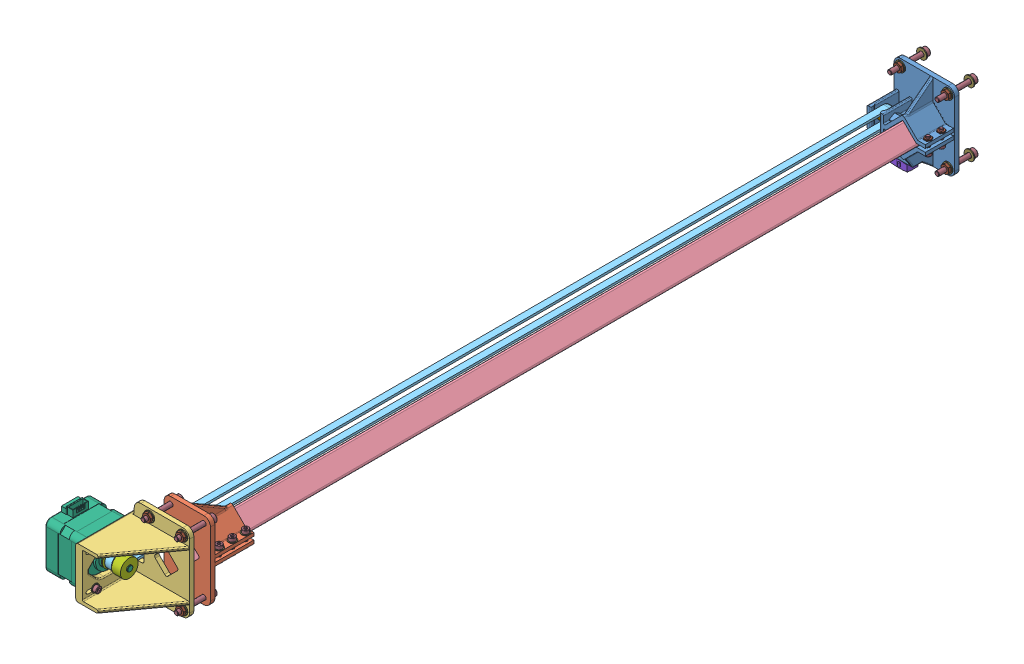
SolidWorks assembly Tower Assy, configuration Default. Lengths in mm.
Overall size (89.12 70.66 764.8).
74 component instances, 13 part files, 76 mates.
Components (placement in the parent):
- tube clamp Top-1: tube clamp Top [Default] at (0 0 -4) x (0 1 0) z (0 0 1) size (70 55 30)
- tube clamp bottom-1: tube clamp bottom [Default] at (0 0 674) x (0 -1 0) z (0 0 -1) size (70 42 40)
- Motor Mount-1: Motor Mount [Default] at (-4 0 689) x (0 1 0) z (0 0 1) size (70 55 52)
- beam-1: beam [Default] x (0.707107 0.707107 0) z (0 0 1) size (19 19 670)
- belt-1: belt [Default] at (-24.75 0 714) x (-1 0 0) z (0 -1 0) size (6 712 14)
- User Library-037_45_074     step motor_-1: User Library-037_45_074     step motor_ [Default] at (-34 0 714) x (-1 0 0) z (0 0 1) size (56 48 42)
- HTPA20S2M060_K_H5_a-1: HTPA20S2M060_K_H5_a [Default] at (-30.5 0 714) x (1 0 0) z (0 0.276501 0.961014) size (18 16 16)
- V4 Microswitch-1: V4 Microswitch [Default] at (-13.75 -30.2 8.3) x (-1 0 0) z (0 1 0) size (19.8 16 6.4)
- radial ball bearing_68_skf-11: radial ball bearing_68_skf [SKF - 623 - 8,SI,NC,8_68] at (-23 0 16) x (-1 0 0) z (0 -0.940463 -0.339896) size (4 10 10)
- radial ball bearing_68_skf-12: radial ball bearing_68_skf [SKF - 623 - 8,SI,NC,8_68] at (-27 0 16) x (-1 0 0) z (0 0.019127 -0.999817) size (4 10 10)
- pan head cross recess screw_din-14: pan head cross recess screw_din [ISO 7045 - M3 x 20 - Z --- 20N] at (-35.4 0 16) x (1 0 0) z (0 0.823751 -0.566952) size (22.35 5.6 5.6)
- hex thin nut chamfered gradeab_din-14: hex thin nut chamfered gradeab_din [Hexagon Thin Nut ISO 4035 - M3 - N] at (-17.5 0 16) x (0 -0.866025 -0.5) z (-1 0 0) size (5.5 6.35 1.8)
- plain washer grade a_din-25: plain washer grade a_din [Washer DIN 125 - A 3.2] at (-32.5 0 16) x (1 0 0) z (0 0.074713 0.997205) size (0.5 7 7)
- plain washer grade a_din-26: plain washer grade a_din [Washer DIN 125 - A 3.2] at (-20.5 0 16) x (1 0 0) z (0 0.074713 0.997205) size (0.5 7 7)
- plain washer grade a_din-27: plain washer grade a_din [Washer DIN 125 - A 3.2] at (-29 0 16) x (1 0 0) z (0 0.074713 0.997205) size (0.5 7 7)
- plain washer grade a_din-28: plain washer grade a_din [Washer DIN 125 - A 3.2] at (-27.5 -15.5 698.5) x (1 0 0) z (0 0.074713 0.997205) size (0.5 7 7)
- socket head cap screw 4762_din-15: socket head cap screw 4762_din [ISO 4762 M3 x 10 --- 10N] at (-24.5 -15.5 698.5) x (-1 0 0) z (0 -0.699814 0.714325) size (13 5.5 5.5)
- plain washer grade a_din-29: plain washer grade a_din [Washer DIN 125 - A 4.3] at (15 29 693.8) x (0 0 1) z (-0.172888 -0.984942 0) size (0.8 9 9)
- socket head cap screw 4762_din-16: socket head cap screw 4762_din [ISO 4762 M4 x 30 --- 20N] at (15 29 665.2) x (0 0 1) z (-0.929203 -0.369569 0) size (34 7 7)
- hex thin nut chamfered gradeab_din-15: hex thin nut chamfered gradeab_din [Hexagon Thin Nut ISO 4035 - M4 - N] at (15 29 696) x (-0.973232 0.229826 0) z (0 0 1) size (7 8.08 2.2)
- plain washer grade a_din-30: plain washer grade a_din [Washer DIN 125 - A 4.3] at (15 29 670) x (0 0 1) z (-0.172888 -0.984942 0) size (0.8 9 9)
- plain washer grade a_din-31: plain washer grade a_din [Washer DIN 125 - A 4.3] at (-15 29 670) x (0 0 1) z (-0.172888 -0.984942 0) size (0.8 9 9)
- plain washer grade a_din-32: plain washer grade a_din [Washer DIN 125 - A 4.3] at (15 -29 670) x (0 0 1) z (-0.172888 -0.984942 0) size (0.8 9 9)
- plain washer grade a_din-33: plain washer grade a_din [Washer DIN 125 - A 4.3] at (-15 -29 670) x (0 0 1) z (-0.172888 -0.984942 0) size (0.8 9 9)
- plain washer grade a_din-34: plain washer grade a_din [Washer DIN 125 - A 4.3] at (-15 29 693.8) x (0 0 1) z (-0.172888 -0.984942 0) size (0.8 9 9)
- plain washer grade a_din-35: plain washer grade a_din [Washer DIN 125 - A 4.3] at (15 -29 693.8) x (0 0 1) z (-0.172888 -0.984942 0) size (0.8 9 9)
- plain washer grade a_din-36: plain washer grade a_din [Washer DIN 125 - A 4.3] at (-15 -29 693.8) x (0 0 1) z (-0.172888 -0.984942 0) size (0.8 9 9)
- hex thin nut chamfered gradeab_din-16: hex thin nut chamfered gradeab_din [Hexagon Thin Nut ISO 4035 - M4 - N] at (-15 29 696) x (-0.973232 0.229826 0) z (0 0 1) size (7 8.08 2.2)
- hex thin nut chamfered gradeab_din-17: hex thin nut chamfered gradeab_din [Hexagon Thin Nut ISO 4035 - M4 - N] at (15 -29 696) x (-0.973232 0.229826 0) z (0 0 1) size (7 8.08 2.2)
- hex thin nut chamfered gradeab_din-18: hex thin nut chamfered gradeab_din [Hexagon Thin Nut ISO 4035 - M4 - N] at (-15 -29 696) x (-0.973232 0.229826 0) z (0 0 1) size (7 8.08 2.2)
- socket head cap screw 4762_din-17: socket head cap screw 4762_din [ISO 4762 M4 x 30 --- 20N] at (-15 29 665.2) x (0 0 1) z (-0.929203 -0.369569 0) size (34 7 7)
- socket head cap screw 4762_din-18: socket head cap screw 4762_din [ISO 4762 M4 x 30 --- 20N] at (15 -29 665.2) x (0 0 1) z (-0.929203 -0.369569 0) size (34 7 7)
- socket head cap screw 4762_din-19: socket head cap screw 4762_din [ISO 4762 M4 x 30 --- 20N] at (-15 -29 665.2) x (0 0 1) z (-0.929203 -0.369569 0) size (34 7 7)
- plain washer grade a_din-37: plain washer grade a_din [Washer DIN 125 - A 3.2] at (-27.5 -15.5 729.5) x (1 0 0) z (0 0.074713 0.997205) size (0.5 7 7)
- plain washer grade a_din-38: plain washer grade a_din [Washer DIN 125 - A 3.2] at (-27.5 15.5 698.5) x (1 0 0) z (0 0.074713 0.997205) size (0.5 7 7)
- plain washer grade a_din-39: plain washer grade a_din [Washer DIN 125 - A 3.2] at (-27.5 15.5 729.5) x (1 0 0) z (0 0.074713 0.997205) size (0.5 7 7)
- socket head cap screw 4762_din-20: socket head cap screw 4762_din [ISO 4762 M3 x 10 --- 10N] at (-24.5 -15.5 729.5) x (-1 0 0) z (0 -0.699814 0.714325) size (13 5.5 5.5)
- socket head cap screw 4762_din-21: socket head cap screw 4762_din [ISO 4762 M3 x 10 --- 10N] at (-24.5 15.5 698.5) x (-1 0 0) z (0 -0.699814 0.714325) size (13 5.5 5.5)
- socket head cap screw 4762_din-22: socket head cap screw 4762_din [ISO 4762 M3 x 10 --- 10N] at (-24.5 15.5 729.5) x (-1 0 0) z (0 -0.699814 0.714325) size (13 5.5 5.5)
- socket head cap screw 4762_din-23: socket head cap screw 4762_din [ISO 4762 M3 x 12 --- 12N] at (16.8191 8 662) x (0 -1 0) z (-0.921576 0 0.388197) size (15 5.5 5.5)
- plain washer grade a_din-40: plain washer grade a_din [Washer DIN 125 - A 3.2] at (16.8191 4.5 662) x (0 -1 0) z (-0.85738 0 -0.514684) size (0.5 7 7)
- hex thin nut chamfered gradeab_din-19: hex thin nut chamfered gradeab_din [Hexagon Thin Nut ISO 4035 - M3 - N] at (16.8191 -5.3 662) x (-0.866025 0 0.5) z (0 -1 0) size (5.5 6.35 1.8)
- plain washer grade a_din-41: plain washer grade a_din [Washer DIN 125 - A 3.2] at (16.8191 4.5 650) x (0 -1 0) z (-0.85738 0 -0.514684) size (0.5 7 7)
- plain washer grade a_din-42: plain washer grade a_din [Washer DIN 125 - A 3.2] at (16.8191 4.5 638) x (0 -1 0) z (-0.85738 0 -0.514684) size (0.5 7 7)
- hex thin nut chamfered gradeab_din-20: hex thin nut chamfered gradeab_din [Hexagon Thin Nut ISO 4035 - M3 - N] at (16.8191 -5.3 650) x (-0.866025 0 0.5) z (0 -1 0) size (5.5 6.35 1.8)
- hex thin nut chamfered gradeab_din-21: hex thin nut chamfered gradeab_din [Hexagon Thin Nut ISO 4035 - M3 - N] at (16.8191 -5.3 638) x (-0.866025 0 0.5) z (0 -1 0) size (5.5 6.35 1.8)
- socket head cap screw 4762_din-24: socket head cap screw 4762_din [ISO 4762 M3 x 12 --- 12N] at (16.8191 8 650) x (0 -1 0) z (-0.921576 0 0.388197) size (15 5.5 5.5)
- socket head cap screw 4762_din-25: socket head cap screw 4762_din [ISO 4762 M3 x 12 --- 12N] at (16.8191 8 638) x (0 -1 0) z (-0.921576 0 0.388197) size (15 5.5 5.5)
- socket head cap screw 4762_din-26: socket head cap screw 4762_din [ISO 4762 M3 x 12 --- 12N] at (16.8191 -8 8) x (0 1 0) z (0.559193 0 0.829037) size (15 5.5 5.5)
- hex thin nut chamfered gradeab_din-22: hex thin nut chamfered gradeab_din [Hexagon Thin Nut ISO 4035 - M3 - N] at (16.8191 3.5 8) x (0 0 1) z (0 -1 0) size (5.5 6.35 1.8)
- plain washer grade a_din-43: plain washer grade a_din [Washer DIN 125 - A 3.2] at (16.8191 -5 8) x (0 -1 0) z (-0.85738 0 -0.514684) size (0.5 7 7)
- plain washer grade a_din-44: plain washer grade a_din [Washer DIN 125 - A 3.2] at (16.8191 -5 20) x (0 -1 0) z (-0.85738 0 -0.514684) size (0.5 7 7)
- hex thin nut chamfered gradeab_din-23: hex thin nut chamfered gradeab_din [Hexagon Thin Nut ISO 4035 - M3 - N] at (16.8191 3.5 20) x (0 0 1) z (0 -1 0) size (5.5 6.35 1.8)
- socket head cap screw 4762_din-27: socket head cap screw 4762_din [ISO 4762 M3 x 12 --- 12N] at (16.8191 -8 20) x (0 1 0) z (0.559193 0 0.829037) size (15 5.5 5.5)
- socket head cap screw 4762_din-28: socket head cap screw 4762_din [ISO 4762 M4 x 30 --- 20N] at (-28 -29 -23.8) x (0 0 1) z (0.194578 0.980887 0) size (34 7 7)
- plain washer grade a_din-45: plain washer grade a_din [Washer DIN 125 - A 4.3] at (-28 -29 -19.8) x (0 0 -1) z (-0.536982 0.843594 0) size (0.8 9 9)
- hex thin nut chamfered gradeab_din-24: hex thin nut chamfered gradeab_din [Hexagon Thin Nut ISO 4035 - M4 - N] at (-28 -29 0.8) x (-0.988084 -0.153918 0) z (0 0 -1) size (7 8.08 2.2)
- hex thin nut chamfered gradeab_din-25: hex thin nut chamfered gradeab_din [Hexagon Thin Nut ISO 4035 - M4 - N] at (15 -29 0.8) x (-0.988084 -0.153918 0) z (0 0 -1) size (7 8.08 2.2)
- hex thin nut chamfered gradeab_din-26: hex thin nut chamfered gradeab_din [Hexagon Thin Nut ISO 4035 - M4 - N] at (15 29 0.8) x (-0.988084 -0.153918 0) z (0 0 -1) size (7 8.08 2.2)
- hex thin nut chamfered gradeab_din-27: hex thin nut chamfered gradeab_din [Hexagon Thin Nut ISO 4035 - M4 - N] at (-28 29 0.8) x (-0.988084 -0.153918 0) z (0 0 -1) size (7 8.08 2.2)
- plain washer grade a_din-46: plain washer grade a_din [Washer DIN 125 - A 4.3] at (15 -29 -19.8) x (0 0 -1) z (-0.536982 0.843594 0) size (0.8 9 9)
- plain washer grade a_din-47: plain washer grade a_din [Washer DIN 125 - A 4.3] at (15 29 -19.8) x (0 0 -1) z (-0.536982 0.843594 0) size (0.8 9 9)
- plain washer grade a_din-48: plain washer grade a_din [Washer DIN 125 - A 4.3] at (-28 29 -19.8) x (0 0 -1) z (-0.536982 0.843594 0) size (0.8 9 9)
- socket head cap screw 4762_din-29: socket head cap screw 4762_din [ISO 4762 M4 x 30 --- 20N] at (15 -29 -23.8) x (0 0 1) z (0.194578 0.980887 0) size (34 7 7)
- socket head cap screw 4762_din-30: socket head cap screw 4762_din [ISO 4762 M4 x 30 --- 20N] at (15 29 -23.8) x (0 0 1) z (0.194578 0.980887 0) size (34 7 7)
- socket head cap screw 4762_din-31: socket head cap screw 4762_din [ISO 4762 M4 x 30 --- 20N] at (-28 29 -23.8) x (0 0 1) z (0.194578 0.980887 0) size (34 7 7)
- plain washer grade a_din-49: plain washer grade a_din [Washer DIN 125 - A 4.3] at (-28 -29 0) x (0 0 -1) z (-0.185185 0.982704 0) size (0.8 9 9)
- plain washer grade a_din-50: plain washer grade a_din [Washer DIN 125 - A 4.3] at (15 -29 0) x (0 0 -1) z (-0.185185 0.982704 0) size (0.8 9 9)
- plain washer grade a_din-51: plain washer grade a_din [Washer DIN 125 - A 4.3] at (15 29 0) x (0 0 -1) z (-0.185185 0.982704 0) size (0.8 9 9)
- plain washer grade a_din-52: plain washer grade a_din [Washer DIN 125 - A 4.3] at (-28 29 0) x (0 0 -1) z (-0.185185 0.982704 0) size (0.8 9 9)
- pan head cross recess screw_din-1: pan head cross recess screw_din [ISO 7045 - M2.5 x 12 - Z --- 12N] at (-9 -35.5 10.5) x (0 1 0) z (-1 0 0) size (14.05 5 5)
- pan head cross recess screw_din-2: pan head cross recess screw_din [ISO 7045 - M2.5 x 12 - Z --- 12N] at (-18.5 -35.5 10.5) x (0 1 0) z (0 0 1) size (14.05 5 5)
- hex thin nut chamfered gradeab_din-28: hex thin nut chamfered gradeab_din [Hexagon Thin Nut ISO 4035 - M2.5 - N] at (-18.5 -24 10.5) x (0 0 1) z (0 -1 0) size (5 5.77 1.6)
- hex thin nut chamfered gradeab_din-29: hex thin nut chamfered gradeab_din [Hexagon Thin Nut ISO 4035 - M2.5 - N] at (-9 -24 10.5) x (0 0 1) z (0 -1 0) size (5 5.77 1.6)
Mates (geometry in assembly coordinates):
- Coincident5: coincident aligned: plane of beam-1 through (0 0 0) normal (0 0 1); plane of assembly through (0 0 0) normal (0 0 1)
- Coincident6: coincident aligned: plane of beam-1; plane of assembly through (0 0 0) normal (1 0 0)
- Coincident7: coincident: point of beam-1; plane of assembly
- Coincident45: coincident anti-aligned: plane of beam-1 through (0 -11.3137 670) normal (0 0 1); plane of tube clamp bottom-1 through (0 0 670) normal (0 0 -1)
- Coincident49: coincident anti-aligned: plane of belt-1 through (-24.75 0 714) normal (0 -1 0); plane of assembly through (0 0 0) normal (0 1 0)
- Concentric25: concentric aligned: cylinder of HTPA20S2M060_K_H5_a-1 through (-11.5 0 714) axis (-1 0 0) radius 2.5; cylinder of User Library-037_45_074     step motor_-1 through (-11.5 0 714) axis (-1 0 0) radius 2.5
- Distance3: distance = 1 mm aligned: plane of HTPA20S2M060_K_H5_a-1 through (-12.5 2.4025 713.3087) normal (1 0 0); plane of User Library-037_45_074     step motor_-1 through (-11.5 0 714) normal (1 0 0)
- Concentric26: concentric anti-aligned: cylinder of belt-1 through (-27.75 0 714) axis (1 0 0) radius 7; cylinder of User Library-037_45_074     step motor_-1 through (-11.5 0 714) axis (-1 0 0) radius 2.5
- Concentric27: concentric aligned: cylinder of radial ball bearing_68_skf-11 through (-2.3625 0 16) axis (-1 0 0) radius 1.5; cylinder of radial ball bearing_68_skf-12 through (-6.3625 0 16) axis (-1 0 0) radius 1.5
- Coincident57: coincident anti-aligned: plane of radial ball bearing_68_skf-11 through (-25 0.5608 14.4482) normal (-1 0 0); plane of radial ball bearing_68_skf-12 through (-25 2.5495 16.0488) normal (1 0 0)
- Concentric29: concentric anti-aligned: cylinder of belt-1 through (-27.75 0 16) axis (1 0 0) radius 5; cylinder of radial ball bearing_68_skf-12 through (-6.3625 0 16) axis (-1 0 0) radius 5
- Concentric30: concentric aligned: cylinder of radial ball bearing_68_skf-12 through (-6.3625 0 16) axis (-1 0 0) radius 1.5; cylinder of pan head cross recess screw_din-14 through (-60.8 0 16) axis (-1 0 0) radius 1.5
- Coincident61: coincident anti-aligned: plane of tube clamp Top-1 through (-32.5 -9.1582 26) normal (-1 0 0); plane of plain washer grade a_din-25 through (-32.5 1.5955 15.8805) normal (1 0 0)
- Concentric31: concentric aligned: cylinder of pan head cross recess screw_din-14 through (-60.8 0 16) axis (-1 0 0) radius 1.5; cylinder of plain washer grade a_din-25 through (-67.425 0 16) axis (-1 0 0) radius 1.6
- Coincident62: coincident anti-aligned: plane of pan head cross recess screw_din-14 through (-33 -0.8504 14.7644) normal (1 0 0); plane of plain washer grade a_din-25 through (-33 3.4902 15.7385) normal (-1 0 0)
- Concentric32: concentric aligned: cylinder of pan head cross recess screw_din-14 through (-60.8 0 16) axis (-1 0 0) radius 1.5; cylinder of hex thin nut chamfered gradeab_din-14 through (-15.7 0 16) axis (-1 0 0) radius 1.25
- Coincident63: coincident anti-aligned: plane of tube clamp Top-1 through (-17.5 -9.1582 26) normal (1 0 0); plane of hex thin nut chamfered gradeab_din-14 through (-17.5 -1.5877 18.75) normal (-1 0 0)
- Concentric33: concentric aligned: line of tube clamp Top-1 through (-8.6782 0 16) axis (-1 0 0); cylinder of pan head cross recess screw_din-14 through (-60.8 0 16) axis (-1 0 0) radius 1.5
- Coincident65: coincident anti-aligned: plane of radial ball bearing_68_skf-12 through (-29 1.6497 16.0316) normal (-1 0 0); plane of plain washer grade a_din-27 through (-29 1.5955 15.8805) normal (1 0 0)
- Coincident66: coincident anti-aligned: plane of radial ball bearing_68_skf-11 through (-21 0.8667 13.6018) normal (1 0 0); plane of plain washer grade a_din-26 through (-21 3.4902 15.7385) normal (-1 0 0)
- Concentric34: concentric aligned: cylinder of radial ball bearing_68_skf-11 through (-2.3625 0 16) axis (-1 0 0) radius 1.5; cylinder of plain washer grade a_din-26 through (-55.425 0 16) axis (-1 0 0) radius 1.6
- Concentric35: concentric aligned: cylinder of radial ball bearing_68_skf-12 through (-6.3625 0 16) axis (-1 0 0) radius 1.5; cylinder of plain washer grade a_din-27 through (-63.925 0 16) axis (-1 0 0) radius 1.6
- Coincident67: coincident anti-aligned: plane of tube clamp Top-1 through (-29.5 -9.1582 26) normal (1 0 0); plane of plain washer grade a_din-27 through (-29.5 3.4902 15.7385) normal (-1 0 0)
- Distance5: distance = 15 mm anti-aligned: plane of tube clamp bottom-1 through (0 0 674) normal (0 0 1); plane of Motor Mount-1 through (-4 0 689) normal (0 0 -1)
- Coincident69: coincident aligned: plane of Motor Mount-1; plane of assembly through (0 0 0) normal (0 1 0)
- Concentric36: concentric anti-aligned: cylinder of tube clamp bottom-1 through (15 29 670) axis (0 0 -1) radius 2.1; cylinder of Motor Mount-1 through (15 29 693) axis (0 0 1) radius 2.1
- Coincident73: coincident anti-aligned: plane of User Library-037_45_074     step motor_-1 through (-34 -21 693) normal (1 0 0); plane of Motor Mount-1 through (-34 -23 741) normal (-1 0 0)
- Parallel7: parallel aligned: plane of Motor Mount-1 through (-4 0 693) normal (0 0 1); plane of User Library-037_45_074     step motor_-1 through (-67.5 21 735) normal (0 0 1)
- Coincident75: coincident anti-aligned: plane of Motor Mount-1 through (-28 -20 741) normal (1 0 0); plane of plain washer grade a_din-28 through (-28 -12.0098 698.2385) normal (-1 0 0)
- Concentric39: concentric anti-aligned: cylinder of User Library-037_45_074     step motor_-1 through (-67.5 -15.5 698.5) axis (1 0 0) radius 1.6; cylinder of plain washer grade a_din-28 through (-62.425 -15.5 698.5) axis (-1 0 0) radius 1.6
- Concentric40: concentric anti-aligned: cylinder of plain washer grade a_din-28 through (-62.425 -15.5 698.5) axis (-1 0 0) radius 1.6; cylinder of socket head cap screw 4762_din-15 through (7.25 -15.5 698.5) axis (1 0 0) radius 1.5
- Coincident76: coincident anti-aligned: plane of plain washer grade a_din-28 through (-27.5 -13.9045 698.3805) normal (1 0 0); plane of socket head cap screw 4762_din-15 through (-27.5 -17.4644 696.5755) normal (-1 0 0)
- Concentric41: concentric anti-aligned: cylinder of Motor Mount-1 through (15 29 693) axis (0 0 1) radius 2.1; cylinder of plain washer grade a_din-29 through (15 29 658.875) axis (0 0 -1) radius 2.15
- Coincident77: coincident anti-aligned: plane of Motor Mount-1 through (-4 0 693) normal (0 0 1); plane of plain washer grade a_din-29 through (10.5678 29.778 693) normal (0 0 -1)
- Concentric42: concentric aligned: cylinder of tube clamp bottom-1 through (15 29 670) axis (0 0 -1) radius 2.1; cylinder of socket head cap screw 4762_din-16 through (15 29 633.45) axis (0 0 -1) radius 2
- Concentric43: concentric anti-aligned: cylinder of socket head cap screw 4762_din-16 through (15 29 633.45) axis (0 0 -1) radius 2; cylinder of hex thin nut chamfered gradeab_din-15 through (15 29 693.8) axis (0 0 1) radius 1.65
- Coincident78: coincident anti-aligned: plane of plain washer grade a_din-29 through (12.8824 29.3717 693.8) normal (0 0 1); plane of hex thin nut chamfered gradeab_din-15 through (21.8126 27.3912 693.8) normal (0 0 -1)
- Concentric44: concentric aligned: cylinder of socket head cap screw 4762_din-16 through (15 29 633.45) axis (0 0 -1) radius 2; cylinder of plain washer grade a_din-30 through (15 29 635.075) axis (0 0 -1) radius 2.15
- Coincident79: coincident anti-aligned: plane of tube clamp bottom-1 through (0 0 670) normal (0 0 -1); plane of plain washer grade a_din-30 through (12.8824 29.3717 670) normal (0 0 1)
- Coincident80: coincident anti-aligned: plane of socket head cap screw 4762_din-16 through (13.7065 32.2522 669.2) normal (0 0 1); plane of plain washer grade a_din-30 through (10.5678 29.778 669.2) normal (0 0 -1)
- Width5: width anti-aligned: plane of beam-1 through (-1.0607 -12.3744 670) normal (-0.707107 -0.707107 0); plane of beam-1 through (12.3744 1.0607 670) normal (0.707107 0.707107 0); plane of tube clamp bottom-1 through (-13.5765 0 634) normal (0.707107 0.707107 0); plane of tube clamp bottom-1 through (0 13.5765 634) normal (-0.707107 -0.707107 0)
- Coincident81: coincident anti-aligned: plane of beam-1; plane of tube clamp Top-1
- Coincident82: coincident anti-aligned: plane of beam-1 through (0 -11.3137 0) normal (0 0 -1); plane of tube clamp Top-1 through (0 0 0) normal (0 0 1)
- Concentric45: concentric aligned: line of tube clamp bottom-1 through (16.8191 12.504 662) axis (0 -1 0); cylinder of hex thin nut chamfered gradeab_din-19 through (16.8191 -3.5 662) axis (0 -1 0) radius 1.25
- Coincident85: coincident anti-aligned: plane of tube clamp bottom-1 through (0 -3.5 674) normal (0 -1 0); plane of hex thin nut chamfered gradeab_din-19 through (15.2314 -3.5 659.25) normal (0 1 0)
- Concentric46: concentric anti-aligned: line of tube clamp bottom-1 through (16.8191 12.504 662) axis (0 -1 0); cylinder of plain washer grade a_din-40 through (16.8191 39.425 662) axis (0 1 0) radius 1.6
- Concentric47: concentric anti-aligned: line of tube clamp bottom-1 through (16.8191 12.504 662) axis (0 -1 0); cylinder of socket head cap screw 4762_din-23 through (16.8191 39.75 662) axis (0 1 0) radius 1.5
- Coincident88: coincident anti-aligned: plane of tube clamp bottom-1 through (13.3191 4.5 634) normal (0 1 0); plane of plain washer grade a_din-40 through (15.9956 4.5 663.3718) normal (0 -1 0)
- Coincident89: coincident anti-aligned: plane of socket head cap screw 4762_din-23 through (17.8866 5 664.5343) normal (0 -1 0); plane of plain washer grade a_din-40 through (15.0177 5 665.0008) normal (0 1 0)
- Concentric48: concentric anti-aligned: line of tube clamp Top-1 through (16.8191 -17.2561 8) axis (0 1 0); cylinder of socket head cap screw 4762_din-26 through (16.8191 -39.75 8) axis (0 -1 0) radius 1.5
- Concentric49: concentric anti-aligned: line of tube clamp Top-1 through (16.8191 -17.2561 8) axis (0 1 0); cylinder of hex thin nut chamfered gradeab_din-22 through (16.8191 5.3 8) axis (0 -1 0) radius 1.25
- Coincident92: coincident anti-aligned: plane of tube clamp Top-1 through (0 3.5 -4) normal (0 1 0); plane of hex thin nut chamfered gradeab_din-22 through (13.6437 3.5 8) normal (0 -1 0)
- Parallel8: parallel anti-aligned: plane of tube clamp Top-1 through (18.479 3.5 5.125) normal (0 0 1); plane of hex thin nut chamfered gradeab_din-22 through (15.2314 5.3 5.25) normal (0 0 -1)
- Concentric50: concentric anti-aligned: cylinder of socket head cap screw 4762_din-26 through (16.8191 -39.75 8) axis (0 -1 0) radius 1.5; cylinder of plain washer grade a_din-43 through (16.8191 29.925 8) axis (0 1 0) radius 1.6
- Coincident94: coincident anti-aligned: plane of tube clamp Top-1 through (13.3191 -4.5 26) normal (0 -1 0); plane of plain washer grade a_din-43 through (15.0177 -4.5 11.0008) normal (0 1 0)
- Coincident95: coincident anti-aligned: plane of socket head cap screw 4762_din-26 through (14.5392 -5 9.5378) normal (0 1 0); plane of plain washer grade a_din-43 through (15.9956 -5 9.3718) normal (0 -1 0)
- Concentric51: concentric anti-aligned: cylinder of tube clamp Top-1 through (-28 -29 0) axis (0 0 1) radius 2.1; cylinder of socket head cap screw 4762_din-28 through (-28 -29 -55.55) axis (0 0 -1) radius 2
- Concentric52: concentric aligned: cylinder of tube clamp Top-1 through (-28 -29 0) axis (0 0 1) radius 2.1; cylinder of plain washer grade a_din-45 through (-28 -29 15.125) axis (0 0 1) radius 2.15
- Coincident97: coincident anti-aligned: plane of socket head cap screw 4762_din-28 through (-24.5669 -29.681 -19.8) normal (0 0 1); plane of plain washer grade a_din-45 through (-29.8137 -30.1545 -19.8) normal (0 0 -1)
- Concentric53: concentric aligned: cylinder of socket head cap screw 4762_din-28 through (-28 -29 -55.55) axis (0 0 -1) radius 2; cylinder of hex thin nut chamfered gradeab_din-24 through (-28 -29 3) axis (0 0 -1) radius 1.65
- Concentric54: concentric anti-aligned: cylinder of socket head cap screw 4762_din-28 through (-28 -29 -55.55) axis (0 0 -1) radius 2; cylinder of plain washer grade a_din-49 through (-28 -29 34.925) axis (0 0 1) radius 2.15
- Coincident98: coincident anti-aligned: plane of hex thin nut chamfered gradeab_din-24 through (-21.0834 -27.9226 0.8) normal (0 0 -1); plane of plain washer grade a_din-49 through (-32.4222 -29.8333 0.8) normal (0 0 1)
- Distance6: distance = 15 mm anti-aligned: plane of plain washer grade a_din-45 through (-31.7962 -31.4164 -19) normal (0 0 1); plane of tube clamp Top-1 through (0 0 -4) normal (0 0 -1)
- Parallel9: parallel aligned: plane of tube clamp Top-1 through (0 0 0) normal (0 0 1); plane of V4 Microswitch-1 through (-3.85 -33.4 18.2) normal (0 0 1)
- Coincident107: coincident anti-aligned: plane of tube clamp Top-1 through (-1.5 -27 18) normal (0 -1 0); plane of V4 Microswitch-1 through (-13.6176 -27 13.1229) normal (0 1 0)
- Concentric56: concentric: point of tube clamp Top-1; cylinder of V4 Microswitch-1 through (-18.5 -30.2 10.5) axis (0 1 0) radius 1.1
- Concentric57: concentric anti-aligned: cylinder of V4 Microswitch-1 through (-18.5 -30.2 10.5) axis (0 1 0) radius 1.1; cylinder of pan head cross recess screw_din-2 through (-18.5 -60.9 10.5) axis (0 -1 0) radius 2.5
- Coincident108: coincident anti-aligned: plane of V4 Microswitch-1 through (-13.6176 -33.4 13.1229) normal (0 -1 0); plane of pan head cross recess screw_din-2 through (-19.75 -33.4 10.5) normal (0 1 0)
- Coincident109: coincident anti-aligned: plane of V4 Microswitch-1 through (-13.6176 -33.4 13.1229) normal (0 -1 0); plane of pan head cross recess screw_din-1 through (-9 -33.4 9.25) normal (0 1 0)
- Concentric58: concentric anti-aligned: cylinder of V4 Microswitch-1 through (-9 -30.2 10.5) axis (0 1 0) radius 1.25; cylinder of pan head cross recess screw_din-1 through (-9 -60.9 10.5) axis (0 -1 0) radius 1.25
- Coincident110: coincident anti-aligned: plane of tube clamp Top-1 through (1.5 -24 18) normal (0 1 0); plane of hex thin nut chamfered gradeab_din-28 through (-21.3868 -24 10.5) normal (0 -1 0)
- Concentric59: concentric aligned: cylinder of pan head cross recess screw_din-2 through (-18.5 -60.9 10.5) axis (0 -1 0) radius 1.25; cylinder of hex thin nut chamfered gradeab_din-28 through (-18.5 -22.4 10.5) axis (0 -1 0) radius 1.025
- Concentric60: concentric aligned: cylinder of pan head cross recess screw_din-1 through (-9 -60.9 10.5) axis (0 -1 0) radius 1.25; cylinder of hex thin nut chamfered gradeab_din-29 through (-9 -22.4 10.5) axis (0 -1 0) radius 1.025
- Coincident111: coincident anti-aligned: plane of tube clamp Top-1 through (1.5 -24 18) normal (0 1 0); plane of hex thin nut chamfered gradeab_din-29 through (-11.8868 -24 10.5) normal (0 -1 0)
- Coincident112: coincident aligned: plane of hex thin nut chamfered gradeab_din-28 through (-19.9434 -22.4 13) normal (0 0 1); plane of hex thin nut chamfered gradeab_din-29 through (-10.4434 -22.4 13) normal (0 0 1)
- Coincident116: coincident anti-aligned: plane of tube clamp Top-1 through (0 0 0) normal (0 0 1); plane of plain washer grade a_din-49 through (-30.1128 -29.3981 0) normal (0 0 -1)
